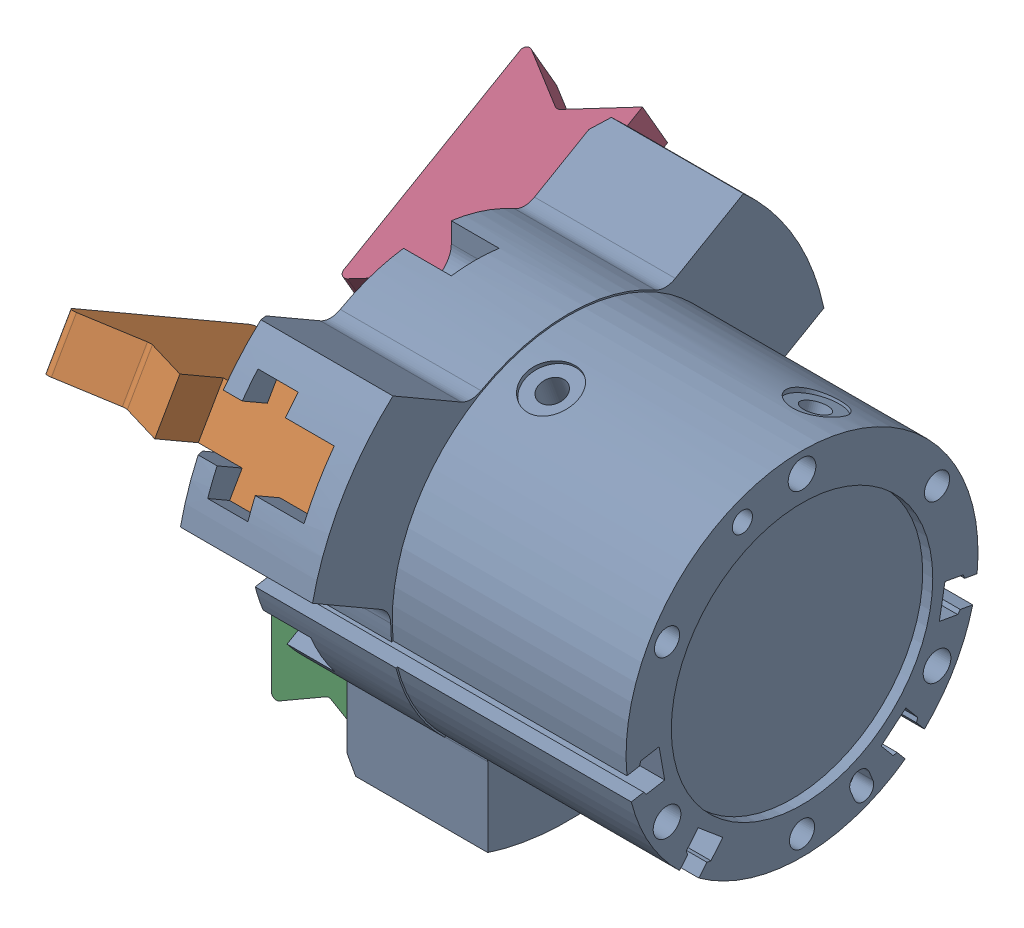
SolidWorks assembly Air_Gripper_Assembly, configuration Default. Lengths in mm.
Overall size (100.53 94.6 107).
4 component instances, 2 part files, 0 mates.
Components (placement in the parent):
- Air_Gripper_Body-1: Air_Gripper_Body [Default] at (2.7288 -0.6305 1.3862) size (74.5 90.6 101.7)
- Air_Gripper_Grip-1: Air_Gripper_Grip [Default] at (-58.2712 16.3695 30.831) x (1 0 0) z (0 0.866025 -0.5) size (49.23 44 20)
- Air_Gripper_Grip-2: Air_Gripper_Grip [Default] at (-58.2712 -34.6305 1.3862) size (49.23 44 20)
- Air_Gripper_Grip-3: Air_Gripper_Grip [Default] at (-58.2712 16.3695 -28.0587) x (1 0 0) z (0 0.866025 0.5) size (49.23 44 20)
